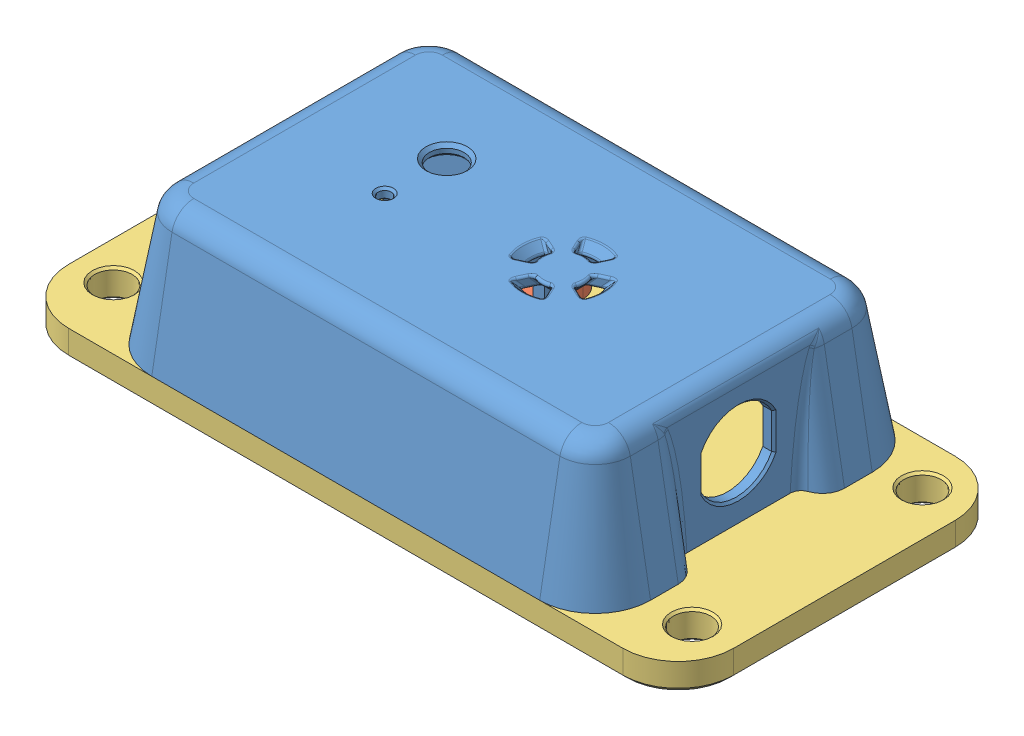
SolidWorks assembly Case Assy, configuration Default. Lengths in mm.
Overall size (76.2 18.41 38.1).
3 component instances, 3 part files, 6 mates.
Components (placement in the parent):
- Case Front-1: Case Front [Default] at origin size (57.15 15.24 38.1)
- Bracket-1: Bracket [Default] at (-5.6698 1.2067 0) x (0 0 -1) z (1 0 0) size (27.62 1.96 4.76)
- Case Back-1: Case Back [Default] at (0 -3.175 0) x (1 0 0) z (0 1 0) size (76.2 38.1 4.45)
Mates (geometry in assembly coordinates):
- Concentric4: concentric aligned: cylinder of Case Front-1 through (-5.6698 15.242 11.43) axis (0 -1 0) radius 0.9652; cylinder of Holder Bracket-1 through (-5.6698 3.1625 11.43) axis (0 -1 0) radius 1.2192
- Coincident19: coincident anti-aligned: plane of Case Front-1 through (0 3.1625 0) normal (0 -1 0); plane of Holder Bracket-1 through (-5.6698 3.1625 11.43) normal (0 1 0)
- Concentric5: concentric aligned: cylinder of Case Front-1 through (-5.6698 15.242 -11.43) axis (0 -1 0) radius 0.9652; cylinder of Holder Bracket-1 through (-5.6698 3.1625 -11.43) axis (0 -1 0) radius 1.2192
- Coincident20: coincident anti-aligned: plane of Case Front-1 through (-22.225 0 12.7) normal (0 -1 0); plane of Case Back - Small Water Pressure Sensor-1 through (0 0 0) normal (0 1 0)
- Concentric6: concentric anti-aligned: cylinder of Case Front-1 through (-24.13 15.242 -14.605) axis (0 -1 0) radius 0.9652; cylinder of Case Back - Small Water Pressure Sensor-1 through (-24.13 -3.175 -14.605) axis (0 1 0) radius 1.5875
- Concentric7: concentric anti-aligned: cylinder of Case Front-1 through (24.13 15.242 14.605) axis (0 -1 0) radius 0.9652; cylinder of Case Back - Small Water Pressure Sensor-1 through (24.13 -3.175 14.605) axis (0 1 0) radius 1.5875
